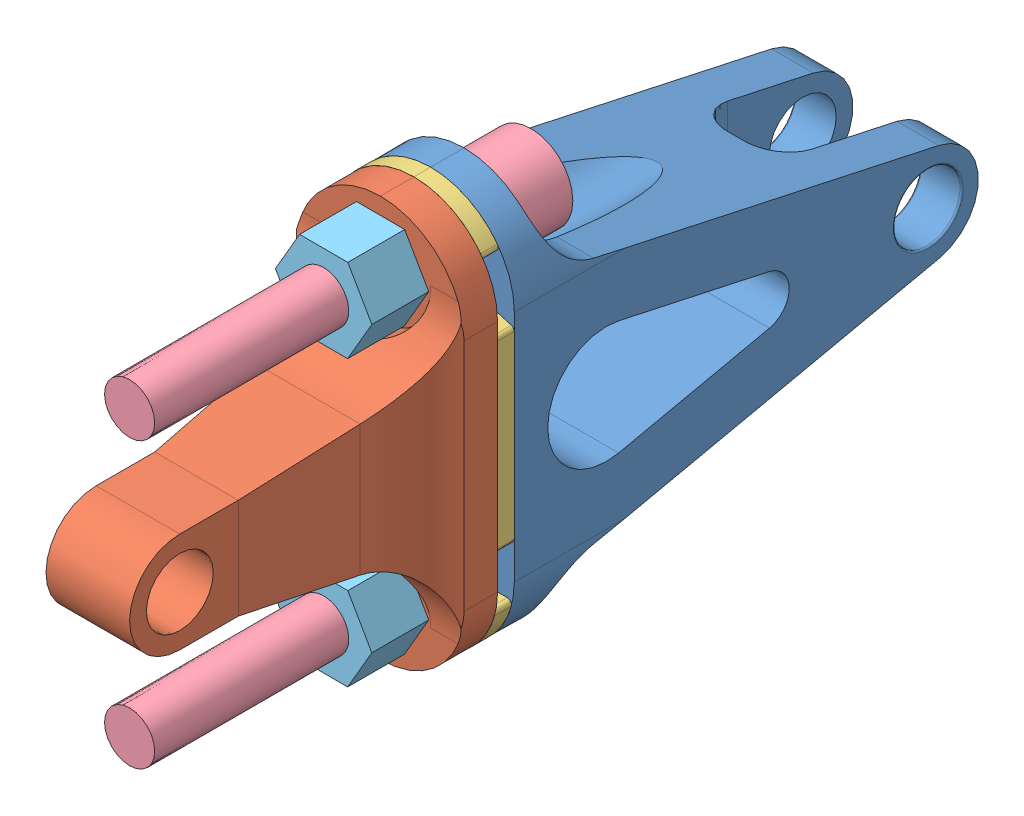
SolidWorks assembly PUTM-S-TR-DI-Regulation-13-49, configuration Domyślna. Lengths in mm.
Overall size (21.13 48 96.5).
7 component instances, 5 part files, 15 mates.
Components (placement in the parent):
- PUTM-S-TR-DI-Insert-Up-1: PUTM-S-TR-DI-Insert-Up [Domyślna] at (2.9316 42.7418 -21.748) x (0 -1 0) z (1 0 0) size (48 55.5 20)
- PUTM-S-TR-DI-Insert-Down-1: PUTM-S-TR-DI-Insert-Down [Domyślna] at (2.9316 3.1828 11.252) size (21.13 48 39)
- PUTM-S-TR-DI-Shim-2mm-1: PUTM-S-TR-DI-Shim-2mm [Domyślna] at (2.9316 27.1828 9.252) x (0 1 0) z (0 0 1) size (48 20 2)
- PUTM-S-TR-DI-M6x40-Bolt-6: PUTM-S-TR-DI-M6x40-Bolt [Domyślna] at (12.9316 20.1828 5.252) x (-1 0 0) z (0 0 -1) size (10 10 48)
- PUTM-S-TR-DI-M6x40-Bolt-7: PUTM-S-TR-DI-M6x40-Bolt [Domyślna] at (12.9316 -13.8172 5.252) x (-1 0 0) z (0 0 -1) size (10 10 48)
- PUTM-S-TR-DI-M6-Nut-5: PUTM-S-TR-DI-M6-Nut [Domyślna] at (12.9316 20.1828 15.252) size (11.53 10 6.8)
- PUTM-S-TR-DI-M6-Nut-6: PUTM-S-TR-DI-M6-Nut [Domyślna] at (12.9316 -13.8172 15.252) size (11.53 10 6.8)
Mates (geometry in assembly coordinates):
- Koncentryczne1: concentric anti-aligned: cylinder of PUTM-H-DI-Insert-Up-1 through (12.9316 20.1828 9.252) axis (0 0 -1) radius 3; cylinder of PUTM-H-DI-Insert-Down-1 through (12.9316 20.1828 11.252) axis (0 0 1) radius 3
- Równolegle1: parallel anti-aligned: cylinder of PUTM-H-DI-Insert-Up-1 through (12.9316 -13.8172 9.252) axis (0 0 -1) radius 3; cylinder of PUTM-H-DI-Insert-Down-1 through (12.9316 -13.8172 11.252) axis (0 0 1) radius 3
- Koncentryczne2: concentric aligned: cylinder of PUTM-H-DI-Insert-Up-1 through (12.9316 20.1828 9.252) axis (0 0 -1) radius 3; cylinder of PUTM-H-DI-shim_2mm-1 through (12.9316 20.1828 11.252) axis (0 0 -1) radius 3
- Koncentryczne3: concentric aligned: cylinder of PUTM-H-DI-Insert-Up-1 through (12.9316 -13.8172 9.252) axis (0 0 -1) radius 3; cylinder of PUTM-H-DI-shim_2mm-1 through (12.9316 -13.8172 11.252) axis (0 0 -1) radius 3
- Wspólnie1: coincident anti-aligned: plane of PUTM-H-DI-Insert-Up-1 through (22.9316 27.1828 9.252) normal (0 0 1); plane of PUTM-H-DI-shim_2mm-1 through (2.9316 27.1828 9.252) normal (0 0 -1)
- Wspólnie2: coincident anti-aligned: plane of PUTM-H-DI-Insert-Down-1 through (22.9316 -20.8172 11.252) normal (0 0 -1); plane of PUTM-H-DI-shim_2mm-1 through (2.9316 27.1828 11.252) normal (0 0 1)
- Koncentryczne12: concentric anti-aligned: cylinder of PUTM-H-DI-Insert-Up-1 through (12.9316 -13.8172 9.252) axis (0 0 -1) radius 3; cylinder of PUTM-H-DI-Insert-Down-1 through (12.9316 -13.8172 11.252) axis (0 0 1) radius 3
- Koncentryczne13: concentric aligned: cylinder of PUTM-H-DI-Insert-Up-1 through (12.9316 20.1828 9.252) axis (0 0 -1) radius 3; cylinder of PUTM-H-DI-M6x40_bolt-6 through (12.9316 20.1828 45.252) axis (0 0 -1) radius 3
- Wspólnie11: coincident anti-aligned: plane of PUTM-H-DI-Insert-Up-1 through (22.9316 27.1828 5.252) normal (0 0 -1); plane of PUTM-H-DI-M6x40_bolt-6 through (12.9316 20.1828 5.252) normal (0 0 1)
- Koncentryczne14: concentric aligned: cylinder of PUTM-H-DI-Insert-Up-1 through (12.9316 -13.8172 9.252) axis (0 0 -1) radius 3; cylinder of PUTM-H-DI-M6x40_bolt-7 through (12.9316 -13.8172 45.252) axis (0 0 -1) radius 3
- Wspólnie12: coincident anti-aligned: plane of PUTM-H-DI-Insert-Up-1 through (22.9316 27.1828 5.252) normal (0 0 -1); plane of PUTM-H-DI-M6x40_bolt-7 through (12.9316 -13.8172 5.252) normal (0 0 1)
- Koncentryczne15: concentric aligned: cylinder of PUTM-H-DI-M6x40_bolt-7 through (12.9316 -13.8172 45.252) axis (0 0 -1) radius 3; cylinder of PUTM-H-DI-M6_nut-6 through (12.9316 -13.8172 26.052) axis (0 0 -1) radius 3
- Wspólnie13: coincident anti-aligned: plane of PUTM-H-DI-Insert-Down-1 through (22.9316 -5.8172 15.252) normal (0 0 1); plane of PUTM-H-DI-M6_nut-6 through (12.9316 -13.8172 15.252) normal (0 0 -1)
- Koncentryczne16: concentric aligned: cylinder of PUTM-H-DI-M6x40_bolt-6 through (12.9316 20.1828 45.252) axis (0 0 -1) radius 3; cylinder of PUTM-H-DI-M6_nut-5 through (12.9316 20.1828 26.052) axis (0 0 -1) radius 3
- Wspólnie14: coincident anti-aligned: plane of PUTM-H-DI-Insert-Down-1 through (22.9316 -5.8172 15.252) normal (0 0 1); plane of PUTM-H-DI-M6_nut-5 through (12.9316 20.1828 15.252) normal (0 0 -1)
